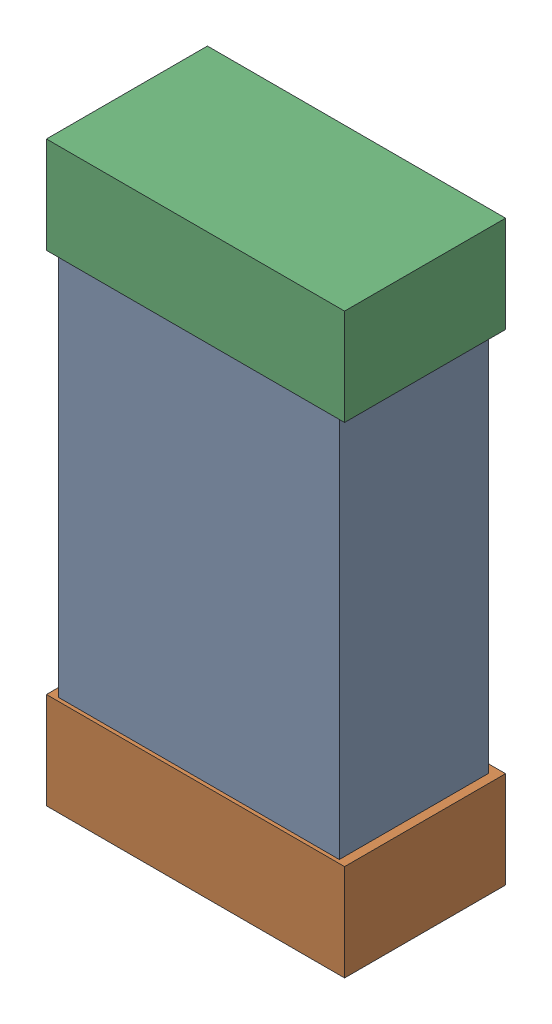
SolidWorks assembly R3, configuration Default. Lengths in mm.
Overall size (0.85 1.65 0.46).
6 component instances, 2 part files, 0 mates.
Components (placement in the parent):
- 432124816_43-1: 432124816_43 [Default] at (37.0957 19.0613 0.025) size (0.8 1.5 0.42)
  - Extruded (1)-1: Extruded (1) [Default] at origin size (0.8 1.5 0.42)
- 432138512_86-1: 432138512_86 [Default] at (37.0957 18.3755 0.001) size (0.85 0.28 0.46)
  - Extruded-1: Extruded [Default] at origin size (0.85 0.28 0.46)
- 432138512_87-1: 432138512_87 [Default] at (37.0957 19.7471 0.001) size (0.85 0.28 0.46)
  - Extruded-1: Extruded [Default] at origin size (0.85 0.28 0.46)
